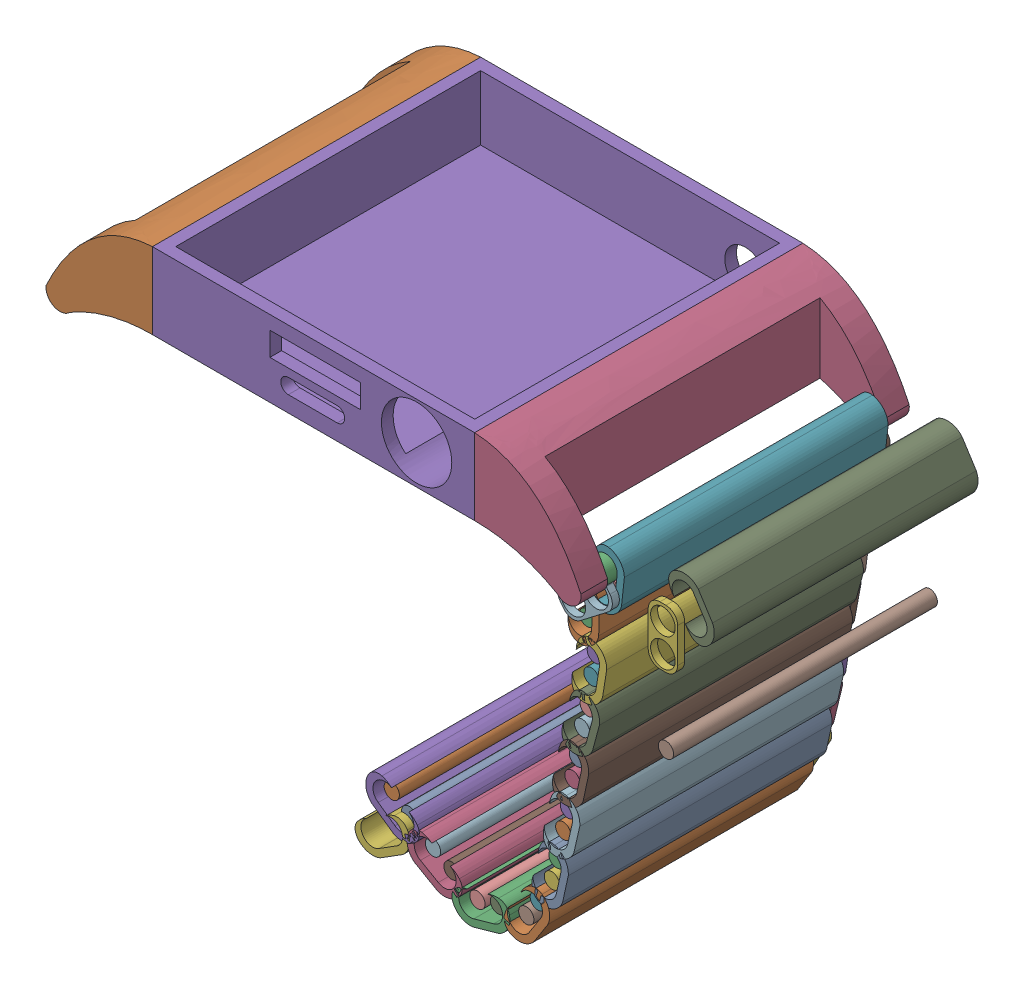
SolidWorks assembly prototype, configuration Default. Lengths in mm.
Overall size (126.98 90.5 73.04).
50 component instances, 4 part files, 96 mates.
Components (placement in the parent):
- Main Base-1: Main Base [Default] at (0.0629 0.1071 -0.106) size (91.28 17.47 56)
- stick spacers-1: stick spacers [Default] at (56.1532 -4.5517 23.1799) size (5.01 9.93 1.2)
- sticks connector-1: sticks connector [Default] at (45.1799 -4.0842 21.4204) x (0 0 1) z (-0.994178 0.107752 0) size (45 10.1 5.28)
- cordon singlular sticks-1: cordon singlular sticks [Default] at (77.2336 -0.3875 -0.0686) size (2.6 2.6 45)
- sticks connector-4: sticks connector [Default] at (77.6779 18.2988 39.6663) x (0 0 1) z (-0.842844 -0.538158 0) size (45 10.1 5.28)
- cordon singlular sticks-3: cordon singlular sticks [Default] at (42.9963 -5.6821 -24.7796) x (0.996628 -0.082051 0) z (0 0 1) size (2.6 2.6 45)
- stick spacers-3: stick spacers [Default] at (41.1127 -7.1338 -24.7796) x (0.610451 -0.792054 0) z (0 0 1) size (5.01 9.93 1.2)
- stick spacers-4: stick spacers [Default] at (41.1127 -7.1338 21.4204) x (0.610451 -0.792054 0) z (0 0 1) size (5.01 9.93 1.2)
- cordon singlular sticks-4: cordon singlular sticks [Default] at (39.1134 -8.6747 -24.7796) x (0.414903 -0.909865 0) z (0 0 1) size (2.6 2.6 45)
- sticks connector-5: sticks connector [Default] at (41.0808 -10.5324 21.4204) x (0 0 1) z (-0.999855 0.017053 0) size (45 10.1 5.28)
- cordon singlular sticks-5: cordon singlular sticks [Default] at (39.0512 -12.322 -24.7796) x (-0.276573 -0.960993 0) z (0 0 1) size (2.6 2.6 45)
- stick spacers-5: stick spacers [Default] at (39.6957 -14.6111 -23.5796) x (-0.962577 -0.271009 0) z (0 0 -1) size (5.01 9.93 1.2)
- cordon singlular sticks-6: cordon singlular sticks [Default] at (40.3798 -17.0408 -24.7796) x (-0.795151 -0.606411 0) z (0 0 1) size (2.6 2.6 45)
- sticks connector-6: sticks connector [Default] at (42.0644 -19.1582 21.4204) x (0 0 1) z (-0.987378 0.158385 0) size (45 10.1 5.28)
- cordon singlular sticks-7: cordon singlular sticks [Default] at (39.802 -20.6426 -24.7796) x (-0.794968 -0.606652 0) z (0 0 1) size (2.6 2.6 45)
- stick spacers-7: stick spacers [Default] at (39.4957 -23.0008 -23.5796) x (-0.991668 0.128819 0) z (0 0 -1) size (5.01 9.93 1.2)
- sticks connector-7: sticks connector [Default] at (40.6227 -27.7871 21.4204) x (0 0 1) z (-0.965198 0.26152 0) size (45 10.1 5.28)
- cordon singlular sticks-8: cordon singlular sticks [Default] at (39.1705 -25.504 -24.7796) x (-0.794904 -0.606736 0) z (0 0 1) size (2.6 2.6 45)
- stick spacers-8: stick spacers [Default] at (37.7819 -31.3629 -24.7796) x (0.983155 -0.182773 0) z (0 0 1) size (5.01 9.93 1.2)
- cordon singlular sticks-9: cordon singlular sticks [Default] at (38.2165 -29.0249 -24.7796) x (-0.93536 0.353697 0) z (0 0 1) size (2.6 2.6 45)
- cordon singlular sticks-10: cordon singlular sticks [Default] at (37.3205 -33.8445 -24.7796) x (-0.935332 0.353772 0) z (0 0 1) size (2.6 2.6 45)
- cordon singlular sticks-11: cordon singlular sticks [Default] at (34.9909 -45.812 -24.7796) x (-0.935258 0.353968 0) z (0 0 1) size (2.6 2.6 45)
- cordon singlular sticks-12: cordon singlular sticks [Default] at (33.8335 -50.5757 -24.7796) x (-0.935157 0.354233 0) z (0 0 1) size (2.6 2.6 45)
- cordon singlular sticks-13: cordon singlular sticks [Default] at (36.5581 -37.4118 -24.7796) x (-0.935148 0.354257 0) z (0 0 1) size (2.6 2.6 45)
- cordon singlular sticks-14: cordon singlular sticks [Default] at (35.8002 -42.2551 -24.7796) x (-0.935241 0.354011 0) z (0 0 1) size (2.6 2.6 45)
- cordon singlular sticks-15: cordon singlular sticks [Default] at (33.0519 -54.1388 -24.7796) x (-0.935065 0.354477 0) z (0 0 1) size (2.6 2.6 45)
- cordon singlular sticks-16: cordon singlular sticks [Default] at (30.6506 -58.4126 -24.7796) x (-0.935544 0.353209 0) z (0 0 1) size (2.6 2.6 45)
- cordon singlular sticks-17: cordon singlular sticks [Default] at (28.6863 -61.4864 -24.7796) x (-0.935262 0.353955 0) z (0 0 1) size (2.6 2.6 45)
- cordon singlular sticks-18: cordon singlular sticks [Default] at (23.8619 -62.3562 -24.7796) x (-0.935195 0.354133 0) z (0 0 1) size (2.6 2.6 45)
- cordon singlular sticks-19: cordon singlular sticks [Default] at (20.3509 -63.3459 -24.7796) x (-0.93515 0.354252 0) z (0 0 1) size (2.6 2.6 45)
- cordon singlular sticks-20: cordon singlular sticks [Default] at (15.9302 -61.227 -24.7796) x (-0.935071 0.35446 0) z (0 0 1) size (2.6 2.6 45)
- cordon singlular sticks-21: cordon singlular sticks [Default] at (12.7682 -59.4082 -24.7796) x (-0.935269 0.353937 0) z (0 0 1) size (2.6 2.6 45)
- cordon singlular sticks-22: cordon singlular sticks [Default] at (8.7111 -56.6565 -24.7796) x (-0.935898 0.352271 0) z (0 0 1) size (2.6 2.6 45)
- cordon singlular sticks-23: cordon singlular sticks [Default] at (5.7334 -54.5492 -24.7796) x (-0.999962 0.008662 0) z (0 0 1) size (2.6 2.6 45)
- cordon singlular sticks-24: cordon singlular sticks [Default] at (6.7607 -59.3426 -24.7796) x (0.881726 -0.471762 0) z (0 0 1) size (2.6 2.6 45)
- stick spacers-9: stick spacers [Default] at (34.4295 -48.1229 -24.7796) x (0.971731 -0.236091 0) z (0 0 1) size (5.01 9.93 1.2)
- stick spacers-10: stick spacers [Default] at (36.1904 -39.7613 -24.7796) x (0.987975 -0.154613 0) z (0 0 1) size (5.01 9.93 1.2)
- stick spacers-11: stick spacers [Default] at (31.887 -56.212 -24.7796) x (0.871813 -0.489838 0) z (0 0 1) size (5.01 9.93 1.2)
- stick spacers-12: stick spacers [Default] at (26.346 -61.9083 -24.7796) x (0.177411 -0.984137 0) z (0 0 1) size (5.01 9.93 1.2)
- stick spacers-13: stick spacers [Default] at (18.2064 -62.3181 -24.7796) x (-0.432231 -0.901763 0) z (0 0 1) size (5.01 9.93 1.2)
- stick spacers-14: stick spacers [Default] at (10.8001 -58.0733 -24.7796) x (-0.56132 -0.827599 0) z (0 0 1) size (5.01 9.93 1.2)
- stick spacers-15: stick spacers [Default] at (6.2318 -56.8745 -24.7796) x (0.977797 0.209553 0) z (0 0 1) size (5.01 9.93 1.2)
- sticks connector-8: sticks connector [Default] at (38.8939 -36.0459 21.4204) x (0 0 1) z (-0.977915 0.209005 0) size (45 10.1 5.28)
- sticks connector-9: sticks connector [Default] at (37.3445 -44.477 21.4204) x (0 0 1) z (-0.975082 0.221846 0) size (45 10.1 5.28)
- sticks connector-10: sticks connector [Default] at (35.395 -52.7855 21.4204) x (0 0 1) z (-0.976774 0.214273 0) size (45 10.1 5.28)
- sticks connector-11: sticks connector [Default] at (31.3527 -61.0258 21.4204) x (0 0 1) z (-0.84264 0.538477 0) size (45 10.1 5.28)
- sticks connector-12: sticks connector [Default] at (22.6487 -64.7748 21.4204) x (0 0 1) z (-0.271333 0.962486 0) size (45 10.1 5.28)
- sticks connector-13: sticks connector [Default] at (13.3526 -62.0502 21.4204) x (0 0 1) z (0.498613 0.866825 0) size (45 10.1 5.28)
- sticks connector-14: sticks connector [Default] at (6.0677 -57.2344 21.4204) x (0 0 1) z (0.577666 0.816273 0) size (45 10.1 5.28)
- sticks connector-15: sticks connector [Default] at (6.279 -62.0052 21.4204) x (0 0 1) z (-0.531807 0.846865 0) size (45 10.1 5.28)
Mates (geometry in assembly coordinates):
- Concentric2: concentric aligned: circle of Main Base-1; circle of sticks connector-1
- Concentric3: concentric anti-aligned: circle of sticks connector-1; circle of cordon singlular sticks-3
- Concentric4: concentric aligned: circle of cordon singlular sticks-3; circle of stick spacers-3
- Coincident6: coincident anti-aligned: plane of sticks connector-1 through (45.1799 -4.0842 -23.5796) normal (0 0 -1); plane of stick spacers-3 through (41.1127 -7.1338 -23.5796) normal (0 0 1)
- Coincident7: coincident aligned: plane of cordon singlular sticks-3 through (42.9963 -5.6821 -24.7796) normal (0 0 -1); plane of stick spacers-3 through (41.1127 -7.1338 -24.7796) normal (0 0 -1)
- Coincident8: coincident anti-aligned: plane of Main Base-1 through (34.9913 11.1071 -23.5796) normal (0 0 1); plane of sticks connector-1 through (45.1799 -4.0842 -23.5796) normal (0 0 -1)
- Concentric5: concentric anti-aligned: circle of sticks connector-1; circle of stick spacers-4
- Coincident10: coincident anti-aligned: plane of sticks connector-1 through (45.1799 -4.0842 21.4204) normal (0 0 1); plane of stick spacers-4 through (41.1127 -7.1338 21.4204) normal (0 0 -1)
- Concentric6: concentric aligned: circle of stick spacers-3; circle of cordon singlular sticks-4
- Concentric7: concentric aligned: circle of stick spacers-4; circle of cordon singlular sticks-4
- Coincident11: coincident aligned: plane of stick spacers-3 through (41.1127 -7.1338 -24.7796) normal (0 0 -1); plane of cordon singlular sticks-4 through (39.1134 -8.6747 -24.7796) normal (0 0 -1)
- Concentric8: concentric aligned: circle of cordon singlular sticks-4; circle of sticks connector-5
- Coincident12: coincident anti-aligned: plane of stick spacers-3 through (41.1127 -7.1338 -23.5796) normal (0 0 1); plane of sticks connector-5 through (41.0808 -10.5324 -23.5796) normal (0 0 -1)
- Concentric9: concentric anti-aligned: circle of sticks connector-5; circle of cordon singlular sticks-5
- Coincident13: coincident aligned: plane of cordon singlular sticks-4 through (39.1134 -8.6747 -24.7796) normal (0 0 -1); plane of cordon singlular sticks-5 through (39.0512 -12.322 -24.7796) normal (0 0 -1)
- Concentric10: concentric anti-aligned: circle of cordon singlular sticks-5; circle of stick spacers-5
- Coincident15: coincident aligned: plane of stick spacers-3 through (41.1127 -7.1338 -24.7796) normal (0 0 -1); plane of stick spacers-5 through (39.6957 -14.6111 -24.7796) normal (0 0 -1)
- Concentric11: concentric anti-aligned: circle of stick spacers-5; circle of cordon singlular sticks-6
- Coincident17: coincident aligned: plane of stick spacers-5 through (39.6957 -14.6111 -24.7796) normal (0 0 -1); plane of cordon singlular sticks-6 through (40.3798 -17.0408 -24.7796) normal (0 0 -1)
- Concentric12: concentric aligned: circle of cordon singlular sticks-6; circle of sticks connector-6
- Coincident18: coincident aligned: plane of sticks connector-5 through (41.0808 -10.5324 -23.5796) normal (0 0 -1); plane of sticks connector-6 through (42.0644 -19.1582 -23.5796) normal (0 0 -1)
- Concentric13: concentric anti-aligned: circle of sticks connector-6; circle of cordon singlular sticks-7
- Coincident19: coincident aligned: plane of cordon singlular sticks-6 through (40.3798 -17.0408 -24.7796) normal (0 0 -1); plane of cordon singlular sticks-7 through (39.802 -20.6426 -24.7796) normal (0 0 -1)
- Coincident20: coincident aligned: plane of stick spacers-5 through (39.6957 -14.6111 -24.7796) normal (0 0 -1); plane of stick spacers-7 through (39.4957 -23.0008 -24.7796) normal (0 0 -1)
- Concentric14: concentric anti-aligned: circle of cordon singlular sticks-7; circle of stick spacers-7
- Concentric15: concentric anti-aligned: circle of stick spacers-7; circle of cordon singlular sticks-8
- Concentric16: concentric aligned: circle of sticks connector-7; circle of cordon singlular sticks-8
- Coincident22: coincident aligned: plane of cordon singlular sticks-7 through (39.802 -20.6426 -24.7796) normal (0 0 -1); plane of cordon singlular sticks-8 through (39.1705 -25.504 -24.7796) normal (0 0 -1)
- Coincident23: coincident aligned: plane of sticks connector-6 through (42.0644 -19.1582 -23.5796) normal (0 0 -1); plane of sticks connector-7 through (40.6227 -27.7871 -23.5796) normal (0 0 -1)
- Coincident25: coincident aligned: plane of cordon singlular sticks-8 through (39.1705 -25.504 -24.7796) normal (0 0 -1); plane of cordon singlular sticks-9 through (38.2165 -29.0249 -24.7796) normal (0 0 -1)
- Concentric18: concentric aligned: circle of stick spacers-8; circle of cordon singlular sticks-9
- Concentric19: concentric anti-aligned: circle of sticks connector-7; circle of cordon singlular sticks-9
- Coincident26: coincident aligned: plane of stick spacers-8 through (37.7819 -31.3629 -24.7796) normal (0 0 -1); plane of cordon singlular sticks-9 through (38.2165 -29.0249 -24.7796) normal (0 0 -1)
- Concentric20: concentric aligned: circle of stick spacers-8; circle of cordon singlular sticks-10
- Concentric21: concentric aligned: circle of cordon singlular sticks-11; circle of stick spacers-9
- Concentric22: concentric aligned: circle of cordon singlular sticks-12; circle of stick spacers-9
- Concentric23: concentric aligned: circle of cordon singlular sticks-13; circle of stick spacers-10
- Concentric24: concentric aligned: circle of cordon singlular sticks-14; circle of stick spacers-10
- Concentric25: concentric aligned: circle of cordon singlular sticks-15; circle of stick spacers-11
- Concentric26: concentric aligned: circle of cordon singlular sticks-14; circle of stick spacers-10
- Concentric27: concentric aligned: circle of cordon singlular sticks-15; circle of stick spacers-11
- Concentric28: concentric aligned: circle of cordon singlular sticks-16; circle of stick spacers-11
- Concentric29: concentric aligned: circle of cordon singlular sticks-16; circle of stick spacers-11
- Concentric30: concentric aligned: circle of cordon singlular sticks-17; circle of stick spacers-12
- Concentric31: concentric aligned: circle of cordon singlular sticks-18; circle of stick spacers-12
- Concentric32: concentric aligned: circle of cordon singlular sticks-19; circle of stick spacers-13
- Concentric33: concentric aligned: circle of cordon singlular sticks-20; circle of stick spacers-13
- Coincident41: coincident anti-aligned: plane of cordon singlular sticks-21 through (12.7682 -59.4082 -24.7796) normal (0 0 -1); circle of stick spacers-14
- Concentric34: concentric aligned: circle of cordon singlular sticks-21; circle of stick spacers-14
- Concentric35: concentric aligned: circle of cordon singlular sticks-22; circle of stick spacers-14
- Concentric36: concentric aligned: circle of cordon singlular sticks-23; circle of stick spacers-15
- Concentric37: concentric aligned: circle of cordon singlular sticks-24; circle of stick spacers-15
- Coincident42: coincident aligned: plane of stick spacers-9 through (34.4295 -48.1229 -24.7796) normal (0 0 -1); plane of stick spacers-10 through (36.1904 -39.7613 -24.7796) normal (0 0 -1)
- Coincident43: coincident aligned: plane of stick spacers-9 through (34.4295 -48.1229 -24.7796) normal (0 0 -1); plane of stick spacers-11 through (31.887 -56.212 -24.7796) normal (0 0 -1)
- Coincident44: coincident aligned: plane of stick spacers-9 through (34.4295 -48.1229 -24.7796) normal (0 0 -1); plane of stick spacers-12 through (26.346 -61.9083 -24.7796) normal (0 0 -1)
- Coincident45: coincident aligned: plane of stick spacers-9 through (34.4295 -48.1229 -24.7796) normal (0 0 -1); plane of stick spacers-13 through (18.2064 -62.3181 -24.7796) normal (0 0 -1)
- Coincident46: coincident aligned: plane of stick spacers-9 through (34.4295 -48.1229 -24.7796) normal (0 0 -1); plane of stick spacers-14 through (10.8001 -58.0733 -24.7796) normal (0 0 -1)
- Coincident47: coincident aligned: plane of stick spacers-9 through (34.4295 -48.1229 -24.7796) normal (0 0 -1); plane of stick spacers-15 through (6.2318 -56.8745 -24.7796) normal (0 0 -1)
- Coincident48: coincident aligned: plane of stick spacers-8 through (37.7819 -31.3629 -24.7796) normal (0 0 -1); plane of stick spacers-10 through (36.1904 -39.7613 -24.7796) normal (0 0 -1)
- Coincident49: coincident aligned: plane of cordon singlular sticks-10 through (37.3205 -33.8445 20.2204) normal (0 0 1); plane of cordon singlular sticks-13 through (36.5581 -37.4118 20.2204) normal (0 0 1)
- Coincident50: coincident aligned: plane of cordon singlular sticks-10 through (37.3205 -33.8445 20.2204) normal (0 0 1); plane of cordon singlular sticks-14 through (35.8002 -42.2551 20.2204) normal (0 0 1)
- Coincident51: coincident aligned: plane of cordon singlular sticks-10 through (37.3205 -33.8445 20.2204) normal (0 0 1); plane of cordon singlular sticks-11 through (34.9909 -45.812 20.2204) normal (0 0 1)
- Coincident52: coincident aligned: plane of cordon singlular sticks-10 through (37.3205 -33.8445 20.2204) normal (0 0 1); plane of cordon singlular sticks-12 through (33.8335 -50.5757 20.2204) normal (0 0 1)
- Coincident53: coincident aligned: plane of cordon singlular sticks-10 through (37.3205 -33.8445 20.2204) normal (0 0 1); plane of cordon singlular sticks-15 through (33.0519 -54.1388 20.2204) normal (0 0 1)
- Coincident54: coincident aligned: plane of cordon singlular sticks-10 through (37.3205 -33.8445 20.2204) normal (0 0 1); plane of cordon singlular sticks-16 through (30.6506 -58.4126 20.2204) normal (0 0 1)
- Coincident55: coincident aligned: plane of cordon singlular sticks-10 through (37.3205 -33.8445 20.2204) normal (0 0 1); plane of cordon singlular sticks-17 through (28.6863 -61.4864 20.2204) normal (0 0 1)
- Coincident56: coincident aligned: plane of cordon singlular sticks-10 through (37.3205 -33.8445 20.2204) normal (0 0 1); plane of cordon singlular sticks-18 through (23.8619 -62.3562 20.2204) normal (0 0 1)
- Coincident57: coincident aligned: plane of cordon singlular sticks-10 through (37.3205 -33.8445 20.2204) normal (0 0 1); plane of cordon singlular sticks-19 through (20.3509 -63.3459 20.2204) normal (0 0 1)
- Coincident58: coincident aligned: plane of cordon singlular sticks-10 through (37.3205 -33.8445 20.2204) normal (0 0 1); plane of cordon singlular sticks-20 through (15.9302 -61.227 20.2204) normal (0 0 1)
- Coincident59: coincident aligned: plane of cordon singlular sticks-10 through (37.3205 -33.8445 20.2204) normal (0 0 1); plane of cordon singlular sticks-22 through (8.7111 -56.6565 20.2204) normal (0 0 1)
- Coincident60: coincident aligned: plane of cordon singlular sticks-10 through (37.3205 -33.8445 20.2204) normal (0 0 1); plane of cordon singlular sticks-23 through (5.7334 -54.5492 20.2204) normal (0 0 1)
- Coincident61: coincident aligned: plane of cordon singlular sticks-10 through (37.3205 -33.8445 20.2204) normal (0 0 1); plane of cordon singlular sticks-24 through (6.7607 -59.3426 20.2204) normal (0 0 1)
- Concentric38: concentric aligned: circle of cordon singlular sticks-12; circle of sticks connector-10
- Concentric39: concentric anti-aligned: circle of cordon singlular sticks-15; circle of sticks connector-10
- Concentric40: concentric aligned: circle of cordon singlular sticks-16; circle of sticks connector-11
- Concentric41: concentric aligned: circle of cordon singlular sticks-10; circle of sticks connector-8
- Concentric42: concentric anti-aligned: circle of cordon singlular sticks-13; circle of sticks connector-8
- Concentric43: concentric aligned: circle of cordon singlular sticks-14; circle of sticks connector-9
- Concentric44: concentric anti-aligned: circle of cordon singlular sticks-11; circle of sticks connector-9
- Concentric45: concentric anti-aligned: circle of cordon singlular sticks-17; circle of sticks connector-11
- Concentric46: concentric aligned: circle of cordon singlular sticks-18; circle of sticks connector-12
- Concentric47: concentric anti-aligned: circle of cordon singlular sticks-19; circle of sticks connector-12
- Concentric48: concentric aligned: circle of cordon singlular sticks-20; circle of sticks connector-13
- Concentric49: concentric anti-aligned: circle of cordon singlular sticks-21; circle of sticks connector-13
- Concentric50: concentric aligned: circle of cordon singlular sticks-22; circle of sticks connector-14
- Concentric51: concentric anti-aligned: circle of cordon singlular sticks-23; circle of sticks connector-14
- Concentric52: concentric aligned: circle of cordon singlular sticks-24; circle of sticks connector-15
- Coincident62: coincident aligned: plane of sticks connector-14 through (6.0677 -57.2344 -23.5796) normal (0 0 -1); plane of sticks connector-15 through (6.279 -62.0052 -23.5796) normal (0 0 -1)
- Coincident63: coincident aligned: plane of sticks connector-13 through (13.3526 -62.0502 -23.5796) normal (0 0 -1); plane of sticks connector-15 through (6.279 -62.0052 -23.5796) normal (0 0 -1)
- Coincident64: coincident aligned: plane of sticks connector-12 through (22.6487 -64.7748 -23.5796) normal (0 0 -1); plane of sticks connector-15 through (6.279 -62.0052 -23.5796) normal (0 0 -1)
- Coincident65: coincident aligned: plane of sticks connector-11 through (31.3527 -61.0258 -23.5796) normal (0 0 -1); plane of sticks connector-15 through (6.279 -62.0052 -23.5796) normal (0 0 -1)
- Coincident66: coincident aligned: plane of sticks connector-10 through (35.395 -52.7855 -23.5796) normal (0 0 -1); plane of sticks connector-15 through (6.279 -62.0052 -23.5796) normal (0 0 -1)
- Coincident67: coincident aligned: plane of sticks connector-9 through (37.3445 -44.477 -23.5796) normal (0 0 -1); plane of sticks connector-15 through (6.279 -62.0052 -23.5796) normal (0 0 -1)
- Coincident68: coincident aligned: plane of sticks connector-8 through (38.8939 -36.0459 -23.5796) normal (0 0 -1); plane of sticks connector-9 through (37.3445 -44.477 -23.5796) normal (0 0 -1)
- Coincident69: coincident aligned: plane of sticks connector-7 through (40.6227 -27.7871 -23.5796) normal (0 0 -1); plane of sticks connector-8 through (38.8939 -36.0459 -23.5796) normal (0 0 -1)
- Coincident70: coincident aligned: plane of cordon singlular sticks-9 through (38.2165 -29.0249 20.2204) normal (0 0 1); plane of cordon singlular sticks-10 through (37.3205 -33.8445 20.2204) normal (0 0 1)
